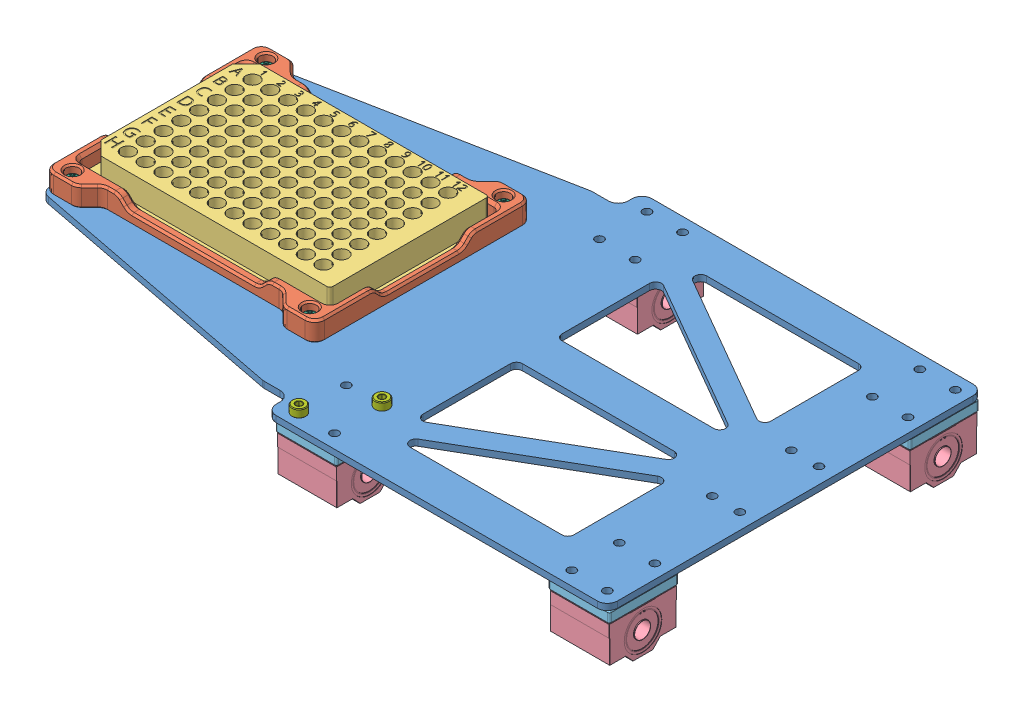
SolidWorks assembly Microplate_Platform_Subassembly, configuration Default. Lengths in mm.
17 component instances, 7 part files, 42 mates.
Components (placement in the parent):
- Microplate_Platform-1: Microplate_Platform [Default] at origin size (325 3.17 190)
- Microplate_Holder-1: Microplate_Holder [Default] at (-94 3.175 0) size (137 10 110)
- Microplate_96_Well.step-1: Microplate_96_Well.step [Default] at (-94 3.175 0) x (1 0 0) z (0 1 0) size (127.76 85.48 14.6)
- Linear_Bearing_SC8UU-1: Linear_Bearing_SC8UU [Default] at (23.4999 -14.7679 76) x (0 0 1) z (0 -1 0) size (34 30.1 22.2)
- Linear_Bearing_SC8UU-2: Linear_Bearing_SC8UU [Default] at (161.4999 -14.7679 76) x (0 0 1) z (0 -1 0) size (34 30.1 22.2)
- Linear_Bearing_SC8UU-3: Linear_Bearing_SC8UU [Default] at (161.4999 -14.7679 -76) x (0 0 1) z (0 -1 0) size (34 30.1 22.2)
- Linear_Bearing_SC8UU-4: Linear_Bearing_SC8UU [Default] at (23.4999 -14.7679 -76) x (0 0 1) z (0 -1 0) size (34 30.1 22.2)
- Bearing_Spacer_Block-1: Bearing_Spacer_Block [Default] at (8.5 -6 76) size (31 6 35)
- Bearing_Spacer_Block-2: Bearing_Spacer_Block [Default] at (146.5 -6 76) size (31 6 35)
- Bearing_Spacer_Block-3: Bearing_Spacer_Block [Default] at (146.5 -6 -76) size (31 6 35)
- Bearing_Spacer_Block-4: Bearing_Spacer_Block [Default] at (8.5 -6 -76) size (31 6 35)
- M3X8_Phillips_Head_Screw-1: M3X8_Phillips_Head_Screw [92000A118] at (-34 5.425 49) x (0.998053 0 0.062367) z (0 1 0) size (6 6 10.46)
- M3X8_Phillips_Head_Screw-2: M3X8_Phillips_Head_Screw [92000A118] at (-154 5.425 -49) x (-0.001865 0 -0.999998) z (0 1 0) size (6 6 10.46)
- M3X8_Phillips_Head_Screw-3: M3X8_Phillips_Head_Screw [92000A118] at (-34 5.425 -49) x (0.014807 0 0.99989) z (0 1 0) size (6 6 10.46)
- M3X8_Phillips_Head_Screw-4: M3X8_Phillips_Head_Screw [92000A118] at (-154 5.425 49) x (0.999995 0 0.003036) z (0 1 0) size (6 6 10.46)
- M4X15 SHCS-1: M4X15 SHCS [91292A354] at (-0.5 -2.325 88) x (0.961097 0 0.276211) z (0 1 0) size (7 7 19.16)
- M4X15 SHCS-2: M4X15 SHCS [91292A354] at (17.5 -2.325 64) x (0.961097 0 0.276211) z (0 1 0) size (7 7 19.16)
Mates (geometry in assembly coordinates):
- Coincident1: coincident anti-aligned: plane of Microplate_Platform-1 through (0 3.175 0) normal (0 1 0); plane of Microplate_Holder-1 through (-94 3.175 0) normal (0 -1 0)
- Concentric1: concentric aligned: cylinder of Microplate_Platform-1 through (-154 3.175 -49) axis (0 1 0) radius 1.25; cylinder of Microplate_Holder-1 through (-154 13.175 -49) axis (0 1 0) radius 1.8
- Concentric2: concentric aligned: cylinder of Microplate_Platform-1 through (-34 3.175 49) axis (0 1 0) radius 1.25; cylinder of Microplate_Holder-1 through (-34 13.175 49) axis (0 1 0) radius 1.8
- LimitDistance1: limit distance = 0 mm anti-aligned: plane of Microplate_Platform-1 through (0 3.175 0) normal (0 1 0); plane of Microplate_96_Well.step-1 through (-94 3.175 0) normal (0 -1 0)
- Width1: width anti-aligned: plane of Microplate_Holder-1 through (-157.93 3.175 42.79) normal (1 0 0); plane of Microplate_96_Well.step-1 through (-30.07 3.175 42.79) normal (-1 0 0); plane of Microplate_Holder-1 through (-157.88 5.675 0) normal (-1 0 0); plane of Microplate_96_Well.step-1 through (-30.12 5.675 0) normal (1 0 0)
- Width2: width anti-aligned: plane of Microplate_Holder-1 through (-157.93 3.175 42.79) normal (0 0 -1); plane of Microplate_96_Well.step-1 through (-157.93 3.175 -42.79) normal (0 0 1); plane of Microplate_Holder-1 through (-94 5.675 42.74) normal (0 0 1); plane of Microplate_96_Well.step-1 through (-94 5.675 -42.74) normal (0 0 -1)
- Concentric3: concentric aligned: cylinder of Microplate_Platform-1 through (-0.5 0 88) axis (0 1 0) radius 2.125; cylinder of Linear_Bearing_SC8UU-1 through (-0.5 -14 88) axis (0 1 0) radius 1.7
- Concentric4: concentric aligned: cylinder of Microplate_Platform-1 through (17.5 0 64) axis (0 1 0) radius 2.125; cylinder of Linear_Bearing_SC8UU-1 through (17.5 -14 64) axis (0 1 0) radius 1.7
- Concentric5: concentric aligned: cylinder of Microplate_Platform-1 through (137.5 0 64) axis (0 1 0) radius 2.125; cylinder of Linear_Bearing_SC8UU-2 through (137.5 -14 64) axis (0 1 0) radius 1.7
- Concentric6: concentric aligned: cylinder of Microplate_Platform-1 through (155.5 0 88) axis (0 1 0) radius 2.125; cylinder of Linear_Bearing_SC8UU-2 through (155.5 -14 88) axis (0 1 0) radius 1.7
- Concentric7: concentric aligned: cylinder of Microplate_Platform-1 through (155.5 0 -64) axis (0 1 0) radius 2.125; cylinder of Linear_Bearing_SC8UU-3 through (155.5 -14 -64) axis (0 1 0) radius 1.7
- Concentric8: concentric aligned: cylinder of Microplate_Platform-1 through (137.5 0 -88) axis (0 1 0) radius 2.125; cylinder of Linear_Bearing_SC8UU-3 through (137.5 -14 -88) axis (0 1 0) radius 1.7
- Concentric9: concentric aligned: cylinder of Microplate_Platform-1 through (-0.5 0 -64) axis (0 1 0) radius 2.125; cylinder of Linear_Bearing_SC8UU-4 through (-0.5 -14 -64) axis (0 1 0) radius 1.7
- Concentric10: concentric aligned: cylinder of Microplate_Platform-1 through (17.5 0 -88) axis (0 1 0) radius 2.125; cylinder of Linear_Bearing_SC8UU-4 through (17.5 -14 -88) axis (0 1 0) radius 1.7
- Coincident3: coincident anti-aligned: plane of Microplate_Platform-1 through (0 0 0) normal (0 -1 0); plane of Bearing_Spacer_Block-1 through (8.5 0 76) normal (0 1 0)
- Coincident4: coincident anti-aligned: plane of Microplate_Platform-1 through (0 0 0) normal (0 -1 0); plane of Bearing_Spacer_Block-2 through (146.5 0 76) normal (0 1 0)
- Coincident5: coincident anti-aligned: plane of Microplate_Platform-1 through (0 0 0) normal (0 -1 0); plane of Bearing_Spacer_Block-3 through (146.5 0 -76) normal (0 1 0)
- Coincident6: coincident anti-aligned: plane of Microplate_Platform-1 through (0 0 0) normal (0 -1 0); plane of Bearing_Spacer_Block-4 through (8.5 0 -76) normal (0 1 0)
- Coincident7: coincident anti-aligned: plane of Linear_Bearing_SC8UU-1 through (33.9019 -6 76) normal (0 1 0); plane of Bearing_Spacer_Block-1 through (8.5 -6 76) normal (0 -1 0)
- Concentric11: concentric aligned: cylinder of Microplate_Platform-1 through (-0.5 0 88) axis (0 1 0) radius 2.125; cylinder of Bearing_Spacer_Block-1 through (-0.5 -6 88) axis (0 1 0) radius 2.2
- Concentric12: concentric aligned: cylinder of Microplate_Platform-1 through (17.5 0 64) axis (0 1 0) radius 2.125; cylinder of Bearing_Spacer_Block-1 through (17.5 -6 64) axis (0 1 0) radius 2.2
- Concentric13: concentric aligned: cylinder of Microplate_Platform-1 through (137.5 0 64) axis (0 1 0) radius 2.125; cylinder of Bearing_Spacer_Block-2 through (137.5 -6 64) axis (0 1 0) radius 2.2
- Concentric14: concentric aligned: cylinder of Microplate_Platform-1 through (155.5 0 88) axis (0 1 0) radius 2.125; cylinder of Bearing_Spacer_Block-2 through (155.5 -6 88) axis (0 1 0) radius 2.2
- Coincident8: coincident anti-aligned: plane of Linear_Bearing_SC8UU-2 through (171.9019 -6 76) normal (0 1 0); plane of Bearing_Spacer_Block-2 through (146.5 -6 76) normal (0 -1 0)
- Coincident9: coincident anti-aligned: plane of Linear_Bearing_SC8UU-3 through (171.9019 -6 -76) normal (0 1 0); plane of Bearing_Spacer_Block-3 through (146.5 -6 -76) normal (0 -1 0)
- Concentric15: concentric aligned: cylinder of Microplate_Platform-1 through (137.5 0 -88) axis (0 1 0) radius 2.125; cylinder of Bearing_Spacer_Block-3 through (137.5 -6 -88) axis (0 1 0) radius 2.2
- Concentric16: concentric aligned: cylinder of Microplate_Platform-1 through (155.5 0 -64) axis (0 1 0) radius 2.125; cylinder of Bearing_Spacer_Block-3 through (155.5 -6 -64) axis (0 1 0) radius 2.2
- Concentric17: concentric aligned: cylinder of Microplate_Platform-1 through (-0.5 0 -88) axis (0 1 0) radius 2.125; cylinder of Bearing_Spacer_Block-4 through (-0.5 -6 -88) axis (0 1 0) radius 2.2
- Concentric18: concentric aligned: cylinder of Microplate_Platform-1 through (17.5 0 -64) axis (0 1 0) radius 2.125; cylinder of Bearing_Spacer_Block-4 through (17.5 -6 -64) axis (0 1 0) radius 2.2
- Coincident10: coincident anti-aligned: plane of Linear_Bearing_SC8UU-4 through (33.9019 -6 -76) normal (0 1 0); plane of Bearing_Spacer_Block-4 through (8.5 -6 -76) normal (0 -1 0)
- Concentric19: concentric aligned: cylinder of Microplate_Holder-1 through (-154 13.175 49) axis (0 1 0) radius 1.8; cylinder of M3X8_Phillips_Head_Screw-4 through (-154 10.675 49) axis (0 1 0) radius 1.5
- Coincident11: coincident anti-aligned: plane of Microplate_Holder-1 through (-152.2 8.175 49) normal (0 1 0); plane of M3X8_Phillips_Head_Screw-4 through (-153.9954 8.175 47.5) normal (0 -1 0)
- Concentric20: concentric aligned: cylinder of Microplate_Holder-1 through (-34 13.175 49) axis (0 1 0) radius 1.8; cylinder of M3X8_Phillips_Head_Screw-1 through (-34 10.675 49) axis (0 1 0) radius 1.5
- Coincident12: coincident anti-aligned: plane of Microplate_Holder-1 through (-32.2 8.175 49) normal (0 1 0); plane of M3X8_Phillips_Head_Screw-1 through (-33.9064 8.175 47.5029) normal (0 -1 0)
- Concentric21: concentric aligned: cylinder of Microplate_Holder-1 through (-154 13.175 -49) axis (0 1 0) radius 1.8; cylinder of M3X8_Phillips_Head_Screw-2 through (-154 10.675 -49) axis (0 1 0) radius 1.5
- Coincident13: coincident anti-aligned: plane of Microplate_Holder-1 through (-152.2 8.175 -49) normal (0 1 0); plane of M3X8_Phillips_Head_Screw-2 through (-155.5 8.175 -48.9972) normal (0 -1 0)
- Concentric22: concentric aligned: cylinder of Microplate_Holder-1 through (-34 13.175 -49) axis (0 1 0) radius 1.8; cylinder of M3X8_Phillips_Head_Screw-3 through (-34 10.675 -49) axis (0 1 0) radius 1.5
- Coincident14: coincident anti-aligned: plane of Microplate_Holder-1 through (-32.2 8.175 -49) normal (0 1 0); plane of M3X8_Phillips_Head_Screw-3 through (-32.5002 8.175 -49.0222) normal (0 -1 0)
- Concentric23: concentric anti-aligned: cylinder of Microplate_Platform-1 through (-0.5 0 88) axis (0 1 0) radius 2.125; cylinder of M4X15 SHCS-1 through (-0.5 -11.825 88) axis (0 -1 0) radius 2
- Coincident15: coincident anti-aligned: plane of Microplate_Platform-1 through (0 3.175 0) normal (0 1 0); plane of M4X15 SHCS-1 through (0.4667 3.175 84.6362) normal (0 -1 0)
- Concentric24: concentric anti-aligned: cylinder of Microplate_Platform-1 through (17.5 0 64) axis (0 1 0) radius 2.125; cylinder of M4X15 SHCS-2 through (17.5 -11.825 64) axis (0 -1 0) radius 2
- Coincident16: coincident anti-aligned: plane of Microplate_Platform-1 through (0 3.175 0) normal (0 1 0); plane of M4X15 SHCS-2 through (18.4667 3.175 60.6362) normal (0 -1 0)
